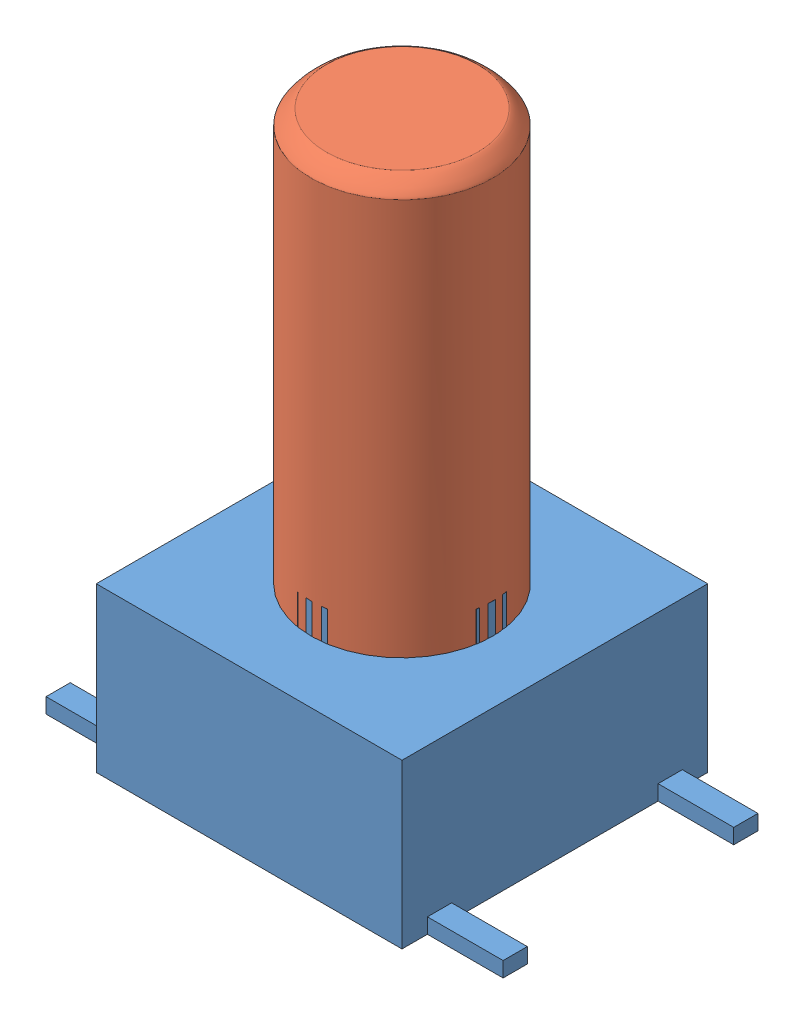
SolidWorks assembly switch, configuration Default. Lengths in mm.
Overall size (15.1 19.01 10.1).
2 component instances, 2 part files, 2 mates.
Components (placement in the parent):
- switch-body-1: switch-body [Default] at (5.8265 4.1464 14.0269) size (15.1 6.4 10.1)
- switch-cap-1: switch-cap [Default] at (5.8265 9.5464 14.0269) x (0.975837 0 0.218502) z (-0.218502 0 0.975837) size (6.14 13.61 6.14)
Mates (geometry in assembly coordinates):
- Concentric1: concentric aligned: circle of switch-body-1; circle of switch-cap-1
- Coincident2: coincident anti-aligned: plane of switch-body-1 through (5.8265 9.5464 14.0269) normal (0 1 0); plane of switch-cap-1 through (5.8265 9.5464 14.0269) normal (0 -1 0)
